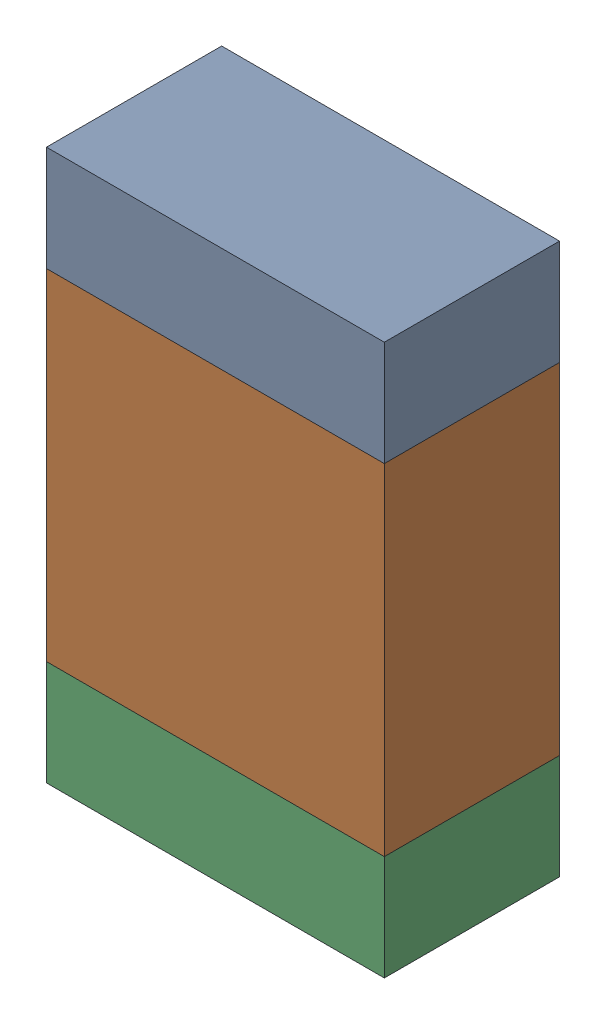
SolidWorks assembly R12-1, configuration Default. Lengths in mm.
Overall size (1.35 2.2 0.7).
6 component instances, 2 part files, 0 mates.
Components (placement in the parent):
- 959207304-1-1: 959207304-1 [Default] at (152.7811 87.2879 0) size (1.35 0.42 0.7)
  - Extruded-39-1: Extruded-39 [Default] at origin size (1.35 0.42 0.7)
- 959207440-1-1: 959207440-1 [Default] at (152.7811 86.3979 0) size (1.35 1.36 0.7)
  - Extruded-40-1: Extruded-40 [Default] at origin size (1.35 1.36 0.7)
- 959207304-1-2: 959207304-1 [Default] at (152.7811 85.5079 0) size (1.35 0.42 0.7)
  - Extruded-39-1: Extruded-39 [Default] at origin size (1.35 0.42 0.7)
